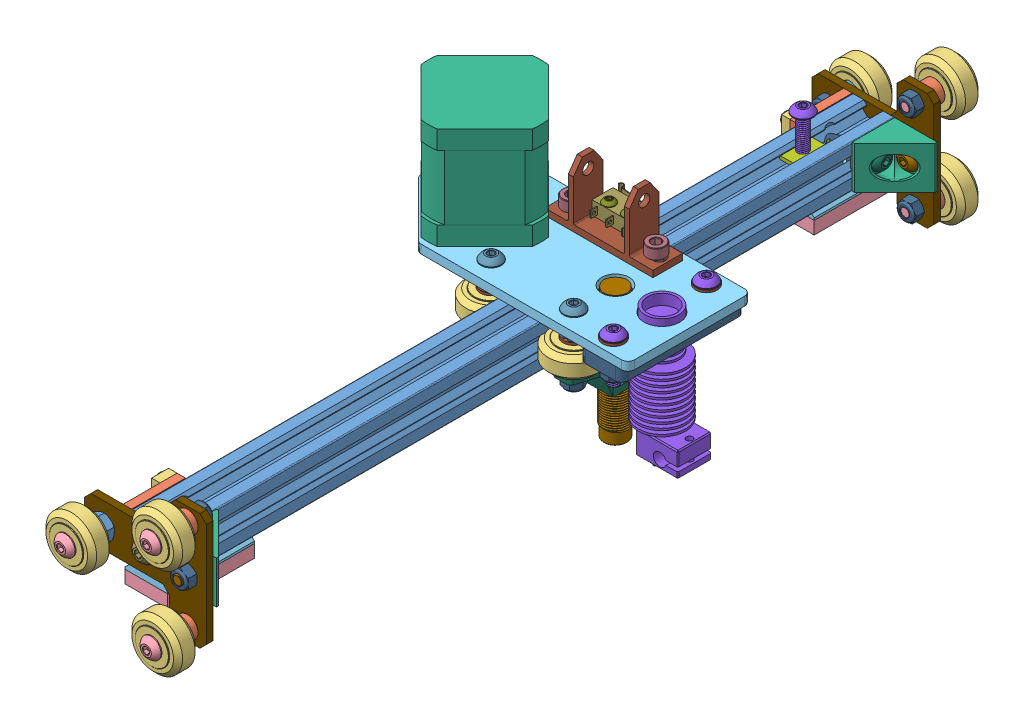
SolidWorks assembly X-100, configuration Default. Lengths in mm.
Overall size (129.03 122.52 385.85).
121 component instances, 33 part files, 9 mates.
Components (placement in the parent):
- X-101-1: X-101 [Default] at (-33.3859 -12.4288 24.8714) size (178.28 120.35 395.31)
  - X-003-1: X-003 [Default] at (3.5883 16.5671 -346.4989) size (20 20 339.65)
  - PX-002_rB-2: PX-002_rB [Default] at (-10.4117 6.5671 -186.1489) x (0 0 1) z (0 -1 0) size (25.4 4 20)
  - PX-003-2: PX-003 [Default] at (-14.4117 6.5671 -168.7489) x (0 0 1) z (0 -1 0) size (8 4 20)
  - PX-004-2: PX-004 [Default] at (-6.4117 3.5671 -189.2239) x (0 0 1) z (-1 0 0) size (41 6 20)
  - PX-005-2: PX-005 [Default] at (-6.4117 6.5671 -189.2239) x (0 0 1) z (-1 0 0) size (41 3 20)
  - PX-006-2: PX-006 [Default] at (23.5883 16.5671 -176.1489) x (0 -1 0) z (0 0 1) size (20 20 20)
  - H-001-2: H-001 [Default] at (3.5883 24.7671 -152.9711) x (0 0 1) z (0 -1 0) size (15 10 3)
  - H-008-1: H-008 [91239A233] at (3.5883 43.2171 -152.9711) x (1 0 0) z (0 1 0) size (9.5 9.5 23.26)
  - H-006-1: H-006 [91239A228] at (3.5883 -5.1829 -156.7239) x (1 0 0) z (0 -1 0) size (9.5 9.5 15.22)
  - H-012-1: H-012 [90576A104] at (23.5883 16.5671 -189.3239) x (-1 0 0) z (0 -1 0) size (8 5.15 9.24)
  - H-011-1: H-011 [93475A240] at (3.5883 16.5671 -189.3239) x (-0.923728 -0.383049 0) z (0 0 -1) size (10 10 1.1)
  - H-001-7: H-001 [Default] at (11.7883 16.5671 -176.1489) x (0 0 1) z (-1 0 0) size (15 10 3)
  - H-007-10: H-007 [91239A232] at (3.5883 16.5671 -193.1739) x (-1 0 0) z (0 0 -1) size (9.5 9.5 19.24)
  - H-006-2: H-006 [91239A228] at (3.5883 -5.1829 -180.7239) x (1 0 0) z (0 -1 0) size (9.5 9.5 15.22)
  - H-015-4: H-015 [Default] at (3.5883 12.7139 -180.7239) x (-1 0 0) z (0 0 1) size (16 6.15 7.7)
  - H-001-5: H-001 [Default] at (3.5883 9.9671 -156.7239) x (0 0 1) z (0 -1 0) size (15 10 3)
  - H-011-5: H-011 [93475A240] at (-11.5117 16.5671 -178.1989) x (0 -0.383049 -0.923728) z (1 0 0) size (10 10 1.1)
  - H-005-1: H-005 [91239A224] at (-14.2617 16.5671 -178.1989) x (0 0 1) z (-1 0 0) size (9.5 9.5 13.21)
  - H-001-6: H-001 [Default] at (-4.6117 16.5671 -178.1989) x (0 0 -1) z (1 0 0) size (15 10 3)
  - H-004-2: H-004 [91239A222] at (19.8383 16.5671 -176.1489) x (0 0 -1) z (1 0 0) size (9.5 9.5 11.19)
  - H-013-1: H-013 [91239A115] at (-16.0617 9.5671 -163.7489) x (0 0 1) z (-1 0 0) size (5.7 5.7 11.96)
  - H-013-2: H-013 [91239A115] at (-16.0617 23.5671 -163.7489) x (0 0 1) z (-1 0 0) size (5.7 5.7 11.96)
  - H-016-1: H-016 [92497A300] at (3.5883 1.5671 -168.7239) x (0.866025 0 -0.5) z (0 1 0) size (8 9.24 4.46)
  - PX-004-3: PX-004 [Default] at (13.5883 3.5671 156.5761) x (0 0 -1) z (1 0 0) size (41 6 20)
  - PX-005-3: PX-005 [Default] at (13.5883 6.5671 156.5761) x (0 0 -1) z (1 0 0) size (41 3 20)
  - PX-003-3: PX-003 [Default] at (-14.4117 26.5671 136.1011) x (0 0 -1) z (0 1 0) size (8 4 20)
  - PX-002_rB-3: PX-002_rB [Default] at (-10.4117 26.5671 153.5011) x (0 0 -1) z (0 1 0) size (25.4 4 20)
  - H-001-8: H-001 [Default] at (-4.6117 16.5671 145.5511) x (0 0 -1) z (1 0 0) size (15 10 3)
  - H-005-2: H-005 [91239A224] at (-14.2617 16.5671 145.5511) x (0 0 -1) z (-1 0 0) size (9.5 9.5 13.21)
  - H-011-6: H-011 [93475A240] at (-10.4117 16.5671 145.5511) x (0 -0.383049 0.923728) z (-1 0 0) size (10 10 1.1)
  - H-001-9: H-001 [Default] at (3.5883 9.9671 124.0761) x (0 0 1) z (0 -1 0) size (15 10 3)
  - H-015-10: H-015 [Default] at (3.5883 12.7139 148.0761) x (1 0 0) z (0 0 -1) size (16 6.15 7.7)
  - H-006-3: H-006 [91239A228] at (3.5883 -5.1829 148.0761) x (1 0 0) z (0 -1 0) size (9.5 9.5 15.22)
  - H-006-4: H-006 [91239A228] at (3.5883 -5.1829 124.0761) x (1 0 0) z (0 -1 0) size (9.5 9.5 15.22)
  - H-013-3: H-013 [91239A115] at (-16.0617 23.5671 131.1011) x (0 0 -1) z (-1 0 0) size (5.7 5.7 11.96)
  - H-013-4: H-013 [91239A115] at (-16.0617 9.5671 131.1011) x (0 0 -1) z (-1 0 0) size (5.7 5.7 11.96)
  - PX-006-3: PX-006 [Default] at (23.5883 16.5671 143.5011) x (0 1 0) z (0 0 -1) size (20 20 20)
  - H-004-3: H-004 [91239A222] at (19.8383 16.5671 143.5011) x (0 0 1) z (1 0 0) size (9.5 9.5 11.19)
  - H-001-11: H-001 [Default] at (11.7883 16.5671 143.5011) x (0 0 1) z (-1 0 0) size (15 10 3)
  - H-006-5: H-006 [91239A228] at (23.5883 16.5671 -179.8989) size (9.5 9.5 15.22)
  - H-012-3: H-012 [90576A104] at (23.5883 16.5671 156.6761) x (1 0 0) z (0 -1 0) size (8 5.15 9.24)
  - H-007-13: H-007 [91239A232] at (3.5883 16.5671 160.5261) x (-1 0 0) z (0 0 1) size (9.5 9.5 19.24)
  - H-011-7: H-011 [93475A240] at (3.5883 16.5671 157.7761) x (-0.923728 -0.383049 0) z (0 0 -1) size (10 10 1.1)
  - H-006-6: H-006 [91239A228] at (23.5883 16.5671 147.2511) x (1 0 0) z (0 0 -1) size (9.5 9.5 15.22)
  - H-016-2: H-016 [92497A300] at (3.5883 1.3792 136.0761) x (0.866025 0 0.5) z (0 -1 0) size (8 9.24 4.46)
- X-102-1: X-102 [Default] at (-38.0825 52.4401 146.4314) x (1 0 0) z (0 -1 0) size (65.73 28.3 66.9)
  - X-002_rB-1: X-002_rB [Default] at (-20.7152 31.941 58.3018) size (57.4 3.17 55)
  - H-002-1: H-002 [Default] at (-11.7152 35.116 48.3018) x (-0.137617 0 0.990486) z (-0.990486 0 -0.137617) size (11.55 8.5 10)
  - H-003-1: H-003 [Default] at (27.9848 35.116 26.8018) x (1 0 0) z (0 1 0) size (10 10 6)
  - H-003-2: H-003 [Default] at (27.9848 35.116 69.8018) x (-1 0 0) z (0 1 0) size (10 10 6)
  - H-014-1: H-014 [Default] at (-12.4976 46.616 48.1931) x (0 -1 0) z (0.120459 0 0.992718) size (11 23.9 23.9)
  - H-014-2: H-014 [Default] at (27.9848 46.616 26.8018) x (0 -1 0) z (0 0 1) size (11 23.9 23.9)
  - H-014-3: H-014 [Default] at (27.9848 46.616 69.8018) x (0 -1 0) z (0 0 1) size (11 23.9 23.9)
  - H-009-1: H-009 [91239A234] at (27.9848 54.866 69.8018) x (1 0 0) z (0 1 0) size (9.5 9.5 28.3)
  - H-012-1: H-012 [90576A104] at (27.9848 31.941 69.8018) x (-0.837169 0 -0.546944) z (-0.546944 0 0.837169) size (8 5.15 9.24)
  - H-009-2: H-009 [91239A234] at (-12.4976 54.866 48.1931) x (0.992718 0 -0.120459) z (0 1 0) size (9.5 9.5 28.3)
  - H-009-3: H-009 [91239A234] at (27.9848 54.866 26.8018) x (1 0 0) z (0 1 0) size (9.5 9.5 28.3)
  - H-012-2: H-012 [90576A104] at (-12.4976 31.941 48.1931) x (-0.896957 0 -0.442117) z (-0.442117 0 0.896957) size (8 5.15 9.24)
  - H-012-3: H-012 [90576A104] at (27.9848 31.941 26.8018) x (-0.837169 0 -0.546944) z (-0.546944 0 0.837169) size (8 5.15 9.24)
- X-102-2: X-102 [Default] at (-38.0825 -44.1635 -129.3366) x (1 0 0) z (0 1 0) size (65.73 28.3 66.9)
  - X-002_rB-1: X-002_rB [Default] at (-20.7152 31.941 58.3018) size (57.4 3.17 55)
  - H-002-1: H-002 [Default] at (-11.7152 35.116 48.3018) x (-0.137617 0 0.990486) z (-0.990486 0 -0.137617) size (11.55 8.5 10)
  - H-003-1: H-003 [Default] at (27.9848 35.116 26.8018) x (1 0 0) z (0 1 0) size (10 10 6)
  - H-003-2: H-003 [Default] at (27.9848 35.116 69.8018) x (-1 0 0) z (0 1 0) size (10 10 6)
  - H-014-1: H-014 [Default] at (-12.4976 46.616 48.1931) x (0 -1 0) z (0.120459 0 0.992718) size (11 23.9 23.9)
  - H-014-2: H-014 [Default] at (27.9848 46.616 26.8018) x (0 -1 0) z (0 0 1) size (11 23.9 23.9)
  - H-014-3: H-014 [Default] at (27.9848 46.616 69.8018) x (0 -1 0) z (0 0 1) size (11 23.9 23.9)
  - H-009-1: H-009 [91239A234] at (27.9848 54.866 69.8018) x (1 0 0) z (0 1 0) size (9.5 9.5 28.3)
  - H-012-1: H-012 [90576A104] at (27.9848 31.941 69.8018) x (-0.837169 0 -0.546944) z (-0.546944 0 0.837169) size (8 5.15 9.24)
  - H-009-2: H-009 [91239A234] at (-12.4976 54.866 48.1931) x (0.992718 0 -0.120459) z (0 1 0) size (9.5 9.5 28.3)
  - H-009-3: H-009 [91239A234] at (27.9848 54.866 26.8018) x (1 0 0) z (0 1 0) size (9.5 9.5 28.3)
  - H-012-2: H-012 [90576A104] at (-12.4976 31.941 48.1931) x (-0.896957 0 -0.442117) z (-0.442117 0 0.896957) size (8 5.15 9.24)
  - H-012-3: H-012 [90576A104] at (27.9848 31.941 26.8018) x (-0.837169 0 -0.546944) z (-0.546944 0 0.837169) size (8 5.15 9.24)
- X-103-1: X-103 [Default] at (-80.4774 -46.0674 -120.434) size (129.03 178.83 67.65)
  - X-001-1: X-001 [Default] at (104.8797 62.8057 100.0571) size (126 4.06 58)
  - E-001-1: E-001 [Default] at (8.3393 66.8697 100.0571) x (0.707107 0 -0.707107) z (0 -1 0) size (42.42 42.42 72)
  - M-001-1: M-001 [Default] at (8.3393 62.1057 100.0571) x (0 -1 0) z (0 0 1) size (17.5 21.5 21.5)
  - M-003-1: M-003 [Default] at (91.8797 48.4557 100.0571) x (-1 0 0) z (0 0 -1) size (26.65 65.6 22.3)
  - E-003-1: E-003 [Default] at (69.9597 5.2057 100.0571) size (12.06 61.21 12.06)
  - PX-007-1: PX-007 [Default] at (81.8797 56.8057 71.0571) x (0 0 1) z (-1 0 0) size (58 6 20)
  - PX-008-1: PX-008 [Default] at (75.7597 66.8697 74.1571) x (-1 0 0) z (0 0 -1) size (51 28.4 14)
  - E-004-1: E-004 [Default] at (48.7854 73.0447 80.0146) x (-1 0 0) z (0 -1 0) size (21.59 18.57 6.35)
  - H-012-1: H-012 [90576A104] at (69.5517 42.3557 80.4806) x (0.986171 0 -0.16573) z (-0.16573 0 -0.986171) size (8 5.15 9.24)
  - H-012-2: H-012 [90576A104] at (70.0172 44.7057 119.745) x (0.99717 0 0.075176) z (0.075176 0 -0.99717) size (8 5.15 9.24) (hidden)
  - H-012-3: H-012 [90576A104] at (30.2597 44.7057 118.9571) x (-0.837169 0 -0.546944) z (-0.546944 0 0.837169) size (8 5.15 9.24)
  - H-012-4: H-012 [90576A104] at (30.2597 44.7057 81.1571) x (-0.837169 0 -0.546944) z (-0.546944 0 0.837169) size (8 5.15 9.24)
  - H-002-1: H-002 [Default] at (69.9597 62.8057 118.9571) x (-0.997345 0 0.072819) z (0.072819 0 0.997345) size (11.55 8.5 10)
  - H-002-2: H-002 [Default] at (69.9597 62.8057 81.1571) x (0.856318 0 -0.51645) z (-0.51645 0 -0.856318) size (11.55 8.5 10)
  - H-003-1: H-003 [Default] at (30.2597 62.8057 81.1571) x (1 0 0) z (0 -1 0) size (10 10 6)
  - H-003-2: H-003 [Default] at (30.2597 56.8057 118.9571) x (-1 0 0) z (0 1 0) size (10 10 6)
  - H-025-1: H-025 [91290A256] at (69.5517 34.8697 80.4806) x (0.603785 0 -0.797147) z (0 -1 0) size (8.5 8.5 40.49)
  - H-025-2: H-025 [91290A256] at (30.2597 34.8697 81.1571) x (-0.947027 0 0.321154) z (0 -1 0) size (8.5 8.5 40.49)
  - H-010-3: H-010 [91239A236] at (30.2597 69.6197 118.9571) x (1 0 0) z (0 1 0) size (9.5 9.5 33.32)
  - H-010-4: H-010 [91239A236] at (70.0172 69.6197 119.745) x (0.33945 0 0.940624) z (0 1 0) size (9.5 9.5 33.32)
  - H-011-1: H-011 [93475A240] at (69.5517 55.7057 80.4806) x (0.518611 0 0.85501) z (0 1 0) size (10 10 1.1)
  - H-011-2: H-011 [93475A240] at (30.2597 55.7057 81.1571) x (-1 0 0) z (0 1 0) size (10 10 1.1)
  - H-011-3: H-011 [93475A240] at (70.0172 55.7057 119.745) x (-0.998643 0 -0.052084) z (0 1 0) size (10 10 1.1)
  - H-011-4: H-011 [93475A240] at (30.2597 55.7057 118.9571) x (-1 0 0) z (0 1 0) size (10 10 1.1)
  - H-014-1: H-014 [Default] at (30.2597 50.2057 81.1571) x (0 1 0) z (0 0 1) size (11 23.9 23.9)
  - H-014-2: H-014 [Default] at (70.0172 50.2057 119.745) x (0 -1 0) z (-0.052084 0 0.998643) size (11 23.9 23.9)
  - H-014-3: H-014 [Default] at (30.2597 50.2057 118.9571) x (0 -1 0) z (0 0 1) size (11 23.9 23.9)
  - H-014-4: H-014 [Default] at (69.5517 50.2057 80.4806) x (0 -1 0) z (-0.957095 0 0.289776) size (11 23.9 23.9)
  - H-008-1: H-008 [91239A233] at (90.9597 70.7197 121.9774) x (1 0 0) z (0 1 0) size (9.5 9.5 23.26)
  - H-008-2: H-008 [91239A233] at (90.9597 70.7197 78.1368) x (1 0 0) z (0 1 0) size (9.5 9.5 23.26)
  - H-011-9: H-011 [93475A240] at (90.9597 67.9697 121.9774) x (0.837169 0 0.546944) z (0 -1 0) size (10 10 1.1)
  - H-011-10: H-011 [93475A240] at (90.9597 67.9697 78.1368) x (0.837169 0 0.546944) z (0 -1 0) size (10 10 1.1)
  - H-012-5: H-012 [90576A104] at (90.9597 55.7057 121.9774) x (-0.837169 0 -0.546944) z (-0.546944 0 0.837169) size (8 5.15 9.24)
  - H-012-6: H-012 [90576A104] at (90.9597 55.7057 78.1368) x (-0.837169 0 -0.546944) z (-0.546944 0 0.837169) size (8 5.15 9.24)
  - H-013-1: H-013 [91239A115] at (8.3393 61.1557 121.9774) x (1 0 0) z (0 -1 0) size (5.7 5.7 11.96)
  - H-013-2: H-013 [91239A115] at (8.3393 61.1557 78.1368) x (1 0 0) z (0 -1 0) size (5.7 5.7 11.96)
  - H-013-3: H-013 [91239A115] at (30.2597 61.1557 100.0571) x (-1 0 0) z (0 -1 0) size (5.7 5.7 11.96)
  - H-013-4: H-013 [91239A115] at (-13.581 61.1557 100.0571) x (-1 0 0) z (0 -1 0) size (5.7 5.7 11.96)
  - H-013-5: H-013 [91239A115] at (53.4457 77.8697 77.1571) x (1 0 0) z (0 1 0) size (5.7 5.7 11.96)
  - H-013-6: H-013 [91239A115] at (44.0737 77.8697 77.1571) x (-1 0 0) z (0 1 0) size (5.7 5.7 11.96)
  - PX-009-1: PX-009 [Default] at (69.7844 43.6057 100.1128) x (-0.011855 0 -0.99993) z (-0.99993 0 0.011855) size (51.27 13 18)
  - H-011-11: H-011 [93475A240] at (70.0172 43.6057 119.745) x (-0.998643 0 -0.052084) z (0 1 0) size (10 10 1.1)
  - H-011-12: H-011 [93475A240] at (69.5517 43.6057 80.4806) x (-0.734915 0 0.678159) z (0 1 0) size (10 10 1.1)
  - H-012-7: H-012 [90576A104] at (70.0172 40.6057 119.745) x (-0.836639 0 -0.547754) z (-0.547754 0 0.836639) size (8 5.15 9.24)
  - H-011-13: H-011 [93475A240] at (90.9597 55.7057 78.1368) x (-0.994567 0 0.104102) z (0 1 0) size (10 10 1.1)
  - H-011-14: H-011 [93475A240] at (90.9597 56.8057 121.9774) x (1 0 0) z (0 -1 0) size (10 10 1.1)
Mates (geometry in assembly coordinates):
- Coincident1: coincident anti-aligned: plane of X-101-1/X-003-1 through (-20.2976 -5.3617 178.3724) normal (0 0 1); plane of X-102-1/X-002_rB-1 through (-58.7976 -5.8617 178.3724) normal (0 0 -1)
- Concentric1: concentric anti-aligned: circle of X-101-1/H-011-7; circle of X-102-1/X-002_rB-1
- Concentric2: concentric anti-aligned: circle of X-101-1/H-006-6; circle of X-102-1/X-002_rB-1
- Coincident2: coincident anti-aligned: plane of X-101-1/PX-006-2 through (0.2024 -5.8617 -161.2776) normal (0 0 -1); plane of X-102-2/X-002_rB-1 through (-58.7976 14.1383 -161.2776) normal (0 0 1)
- Concentric3: concentric anti-aligned: circle of X-101-1/PX-006-2; circle of X-102-2/X-002_rB-1
- Concentric4: concentric anti-aligned: cylinder of X-101-1/H-011-1 through (-29.7976 4.1383 -165.5526) axis (0 0 1) radius 5; circle of X-102-2/X-002_rB-1
- Parallel1: parallel anti-aligned: plane of X-101-1/X-003-1 through (-39.2976 14.1383 178.3724) normal (0 1 0); plane of X-103-1/X-001-1 through (21.4024 16.7383 -46.3769) normal (0 -1 0)
- Symmetric1: symmetric aligned: plane of X-103-1/H-014-1 through (-50.2177 9.6383 -39.2769) normal (0 1 0); plane of X-103-1/H-014-1 through (-50.2177 -1.3617 -39.2769) normal (0 -1 0); plane of assembly through (0 4.1383 0) normal (0 1 0)
- Distance2: distance = 44.2 mm aligned: plane of X-103-1/X-001-1 through (24.4024 20.8023 -46.3769) normal (1 0 0); plane of X-101-1/X-003-1 through (-19.7976 13.6383 178.3724) normal (1 0 0)
